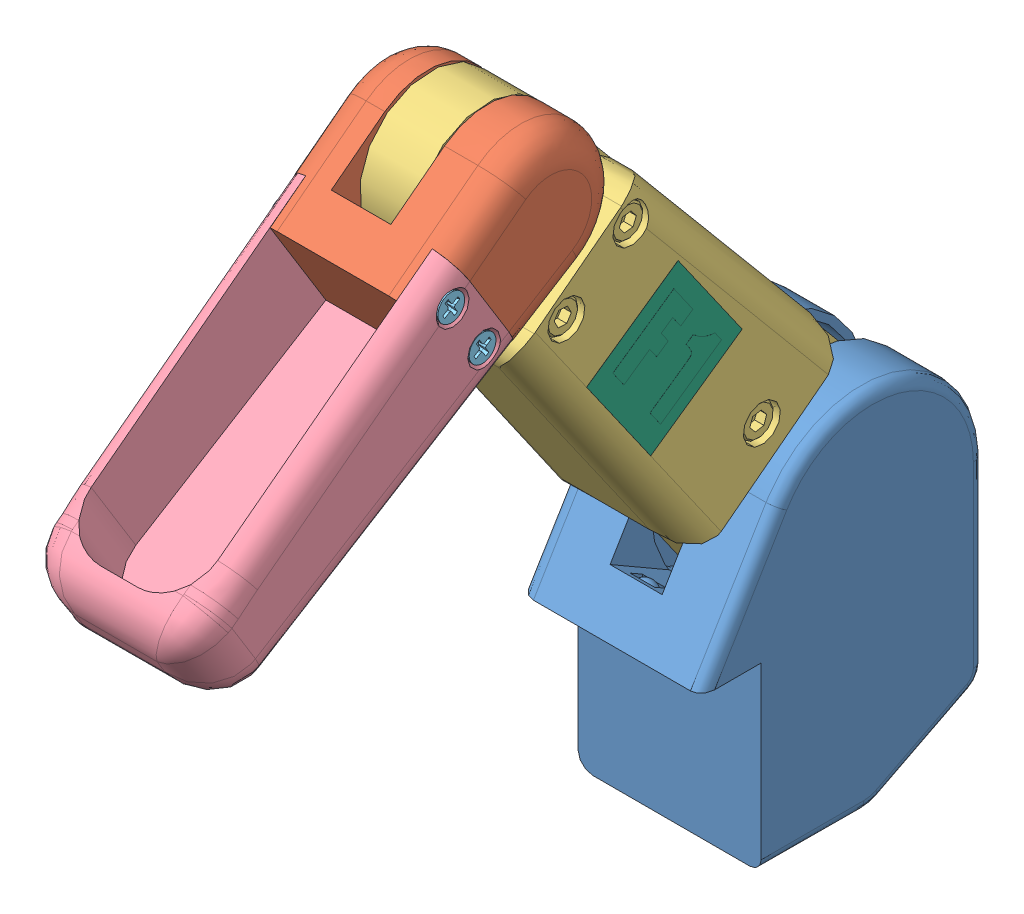
SolidWorks assembly B2587, configuration F1. Lengths in mm.
Overall size (24.6 104.22 112.16).
15 component instances, 8 part files, 31 mates.
Components (placement in the parent):
- B2583-1: B2583 [Default] at origin size (24.6 48.5 38)
- B2584-1: B2584 [Default] at (0 55.5766 42.5587) x (1 0 0) z (0 -0.524977 0.851117) size (23 19 25.5)
- B2585-1: B2585 [Default] x (1 0 0) z (0 0.793951 0.607982) size (19.77 26.65 92)
- B2586-1: B2586 [Default] at (0.1 18.0923 85.234) x (1 0 0) z (0 -0.524977 0.851117) size (23.31 17.9 46)
  - B0926-1: B0926 [Default] at (0 0 -46) x (-1 0 0) z (0 1 0) size (23.31 46 17.9)
  - B1090-1: B1090 [M2-.4x6] at (10.3 13.5 -43) x (-1 0 0) z (0 0 1) size (6 3.6 3.6)
  - B1090-2: B1090 [M2-.4x6] at (10.3 5.5 -43) x (-1 0 0) z (0 -1 0) size (6 3.6 3.6)
  - B1090-3: B1090 [M2-.4x6] at (-10.3 5.5 -43) size (6 3.6 3.6)
  - B1090-4: B1090 [M2-.4x6] at (-10.3 13.5 -43) x (1 0 0) z (0 -1 0) size (6 3.6 3.6)
- B0990-1: B0990 [Default] at (9.85 30.4111 25.5623) x (0 -0.819152 -0.573576) z (1 0 0)
- B0990-2: B0990 [Default] at (-9.75 30.9368 25.9304) x (0 0.819152 0.573576) z (-1 0 0)
- B0991-1: B0991 [Default] at (-9.75 3.4963 -40.215) x (0 0 -1) z (-1 0 0) size (15 15 0.02) (suppressed, hidden)
- B0991-2: B0991 [Default] at (9.85 3.4963 -40.215) x (0 0 1) z (1 0 0) size (15 15 0.02) (suppressed, hidden)
- B0992-1: B0992 [Default] at (-9.75 36.5754 -17.0796) x (0 0.866025 -0.5) z (-1 0 0) (suppressed, hidden)
- B0992-2: B0992 [Default] at (9.85 36.5754 -17.0796) x (0 -0.866025 0.5) z (1 0 0) (suppressed, hidden)
Mates (geometry in assembly coordinates):
- Coincident5: coincident aligned: axis of B2583-1 through (-10.3 0 0) axis (1 0 0); axis of B2585-1 through (-3 0 0) axis (1 0 0)
- Coincident6: coincident aligned: plane of B2583-1; plane of B2585-1
- Concentric3: concentric anti-aligned: cylinder of B2585-1 through (2.9 55.5766 42.5587) axis (-1 0 0) radius 9.5; cylinder of B2584-1 through (-7.4 55.5766 42.5587) axis (1 0 0) radius 9.5
- Coincident7: coincident aligned: plane of B2585-1; plane of B2584-1
- Coincident8: coincident anti-aligned: plane of B2584-1 through (11.6 44.7945 47.6575) normal (0 -0.524977 0.851117); plane of B2586-1/B0926-1 through (11.6 57.4762 55.4797) normal (0 0.524977 -0.851117)
- Coincident9: coincident anti-aligned: plane of B2584-1 through (-11.4 41.6447 52.7642) normal (0 -0.851117 -0.524977); plane of B2586-1/B0926-1 through (5.6 23.7955 81.7022) normal (0 0.851117 0.524977)
- Coincident10: coincident anti-aligned: plane of B2584-1 through (8.6 57.5774 55.5421) normal (1 0 0); plane of B2586-1/B0926-1 through (8.6 3.6771 22.2959) normal (-1 0 0)
- Coincident23: coincident anti-aligned: plane of B2585-1 through (9.85 5.5131 19.1155) normal (1 0 0); plane of B0990-1 through (9.85 32.2529 36.0078) normal (-1 0 0)
- Coincident11: coincident aligned: line of B2585-1 through (9.85 42.0917 42.897) axis (0 -0.819152 -0.573576); line of B0990-1 through (9.85 32.2529 36.0078) axis (0 -0.819152 -0.573576)
- Coincident13: coincident anti-aligned: plane of B2585-1 through (-9.75 5.5131 19.1155) normal (-1 0 0); plane of B0990-2
- Coincident14: coincident aligned: line of B2585-1 through (-9.75 6.429 17.9257) axis (0 0.819152 0.573576); line of B0990-2 through (-9.75 20.4914 27.7722) axis (0 0.819152 0.573576)
- Coincident15: coincident anti-aligned: plane of B2585-1 through (9.85 3.8915 19.5103) normal (1 0 0); plane of B0991-2 through (9.85 38.8226 27.1432) normal (-1 0 0)
- Coincident16: coincident anti-aligned: plane of B2585-1 through (-9.75 3.8915 19.5103) normal (-1 0 0); plane of B0991-1 through (-9.75 27.2997 17.5399) normal (1 0 0)
- Coincident17: coincident aligned: line of B2585-1 through (-9.75 6.429 17.9257) axis (0 0.819152 0.573576); line of B0991-1
- Coincident18: coincident aligned: line of B2585-1 through (9.85 42.0917 42.897) axis (0 -0.819152 -0.573576); line of B0991-2
- Coincident19: coincident anti-aligned: plane of assembly through (9.85 3.6871 19.55) normal (1 0 0)
- Coincident20: coincident anti-aligned: plane of assembly through (-9.75 3.6871 19.55) normal (-1 0 0)
- Coincident21: coincident aligned: line of B2585-1 through (9.85 42.0917 42.897) axis (0 -0.819152 -0.573576); line of B0992-2
- Coincident22: coincident aligned: line of B2585-1 through (-9.75 6.429 17.9257) axis (0 0.819152 0.573576); line of B0992-1
- J12: planar angle = 2.181662 rad aligned: plane of B2583-1 through (-12.3 -9.1 23) normal (0 -1 0); plane of B2585-1 through (3.85 3.9915 21.102) normal (0 -0.573576 0.819152)
- J13: planar angle = 1.512619 rad anti-aligned: plane of B2585-1 through (3.85 3.9915 21.102) normal (0 -0.573576 0.819152); plane of B2586-1/B0926-1 through (5.6 21.2421 80.1273) normal (0 -0.851117 -0.524977)
- J22: planar angle = 2.181662 rad aligned: plane of assembly through (-12.3 -9.1 23) normal (0 -1 0)
- J23: planar angle = 1.512619 rad anti-aligned: plane of B2585-1; plane of B2586-1/B0926-1
- J32: planar angle = 2.181662 rad aligned: plane of assembly through (-12.3 -9.1 23) normal (0 -1 0)
- J33: planar angle = 1.512619 rad anti-aligned: plane of B2585-1; plane of B2586-1/B0926-1
- Coincident26: coincident: plane of B2585-1; point of B0990-1
- Coincident27: coincident: plane of B2585-1; point of B0990-2
- Coincident29: coincident: plane of B2585-1; point of B0991-2
- Coincident32: coincident: plane of B2585-1; point of B0991-1
- Coincident33: coincident: plane of B2585-1; point of B0992-2
- Coincident34: coincident: plane of B2585-1; point of B0992-1
